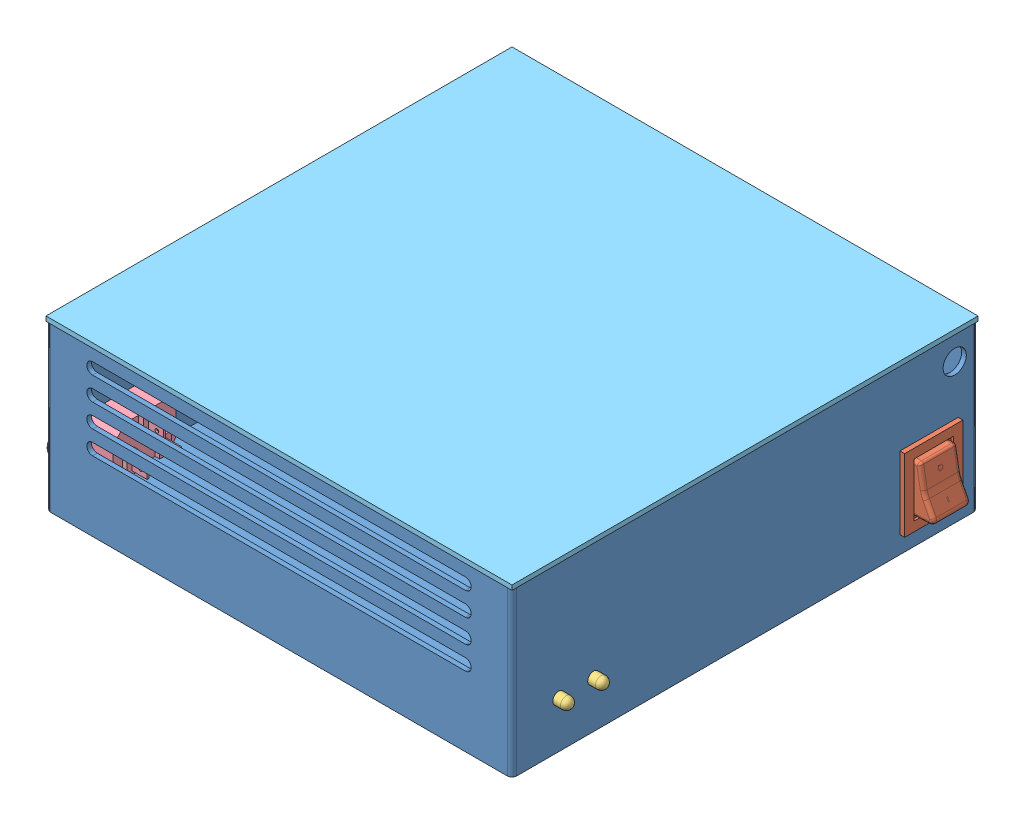
SolidWorks assembly Assem1, configuration Default. Lengths in mm.
Overall size (214.38 72 200).
6 component instances, 5 part files, 13 mates.
Components (placement in the parent):
- base-1: base [Default] at (154.8704 54.4764 92.3221) size (200 70 200)
- KCD4_ROCKET_SWITCH-1: KCD4_ROCKET_SWITCH [Default] at (156.8704 77.4764 113.3221) x (0 0 1) z (0 1 0) size (25 37.48 33.2)
- LED 5mm-1: LED 5mm [Valor predeterminado] at (151.8704 74.4764 257.3221) x (0 -1 0) z (1 0 0) size (10.06 6 40.8)
- LED 5mm-2: LED 5mm [Valor predeterminado] at (151.8704 74.4764 272.3221) x (0 1 0) z (1 0 0) size (10.06 6 40.8)
- AC Power outlet connector-1: AC Power outlet connector [Default] at (-48.4296 74.0764 263.8221) x (0 0 1) z (-1 0 0) size (50 22.4 26.9)
- cover-1: cover [Default] at (148.6869 124.4764 142.5254) size (200 2 200)
Mates (geometry in assembly coordinates):
- Coincident2: coincident anti-aligned: plane of base-1 through (147.8704 90.4764 102.3221) normal (0 0 1); plane of KCD4_ROCKET_SWITCH-1 through (137.1704 90.4764 102.3221) normal (0 0 -1)
- Coincident3: coincident anti-aligned: plane of base-1 through (147.8704 90.4764 124.3221) normal (0 -1 0); plane of KCD4_ROCKET_SWITCH-1 through (137.1704 90.4764 124.3221) normal (0 1 0)
- Coincident4: coincident anti-aligned: plane of base-1 through (154.8704 124.4764 92.3221) normal (1 0 0); plane of KCD4_ROCKET_SWITCH-1 through (154.8704 77.4764 113.3221) normal (-1 0 0)
- Concentric1: concentric anti-aligned: cylinder of base-1 through (147.8704 74.4764 257.3221) axis (1 0 0) radius 2.5; cylinder of LED 5mm-1 through (152.8704 74.4764 257.3221) axis (-1 0 0) radius 2.5
- Coincident6: coincident anti-aligned: plane of base-1 through (152.8704 124.4764 92.3221) normal (-1 0 0); plane of LED 5mm-1 through (152.8704 74.4764 257.3221) normal (1 0 0)
- Concentric2: concentric anti-aligned: cylinder of base-1 through (147.8704 74.4764 272.3221) axis (1 0 0) radius 2.5; cylinder of LED 5mm-2 through (152.8704 74.4764 272.3221) axis (-1 0 0) radius 2.5
- Coincident7: coincident anti-aligned: plane of base-1 through (152.8704 124.4764 92.3221) normal (-1 0 0); plane of LED 5mm-2 through (152.8704 74.4764 272.3221) normal (1 0 0)
- Coincident8: coincident anti-aligned: plane of base-1 through (-38.1296 83.4764 277.3221) normal (0 0 -1); plane of AC Power outlet connector-1 through (-31.3296 64.6764 277.3221) normal (0 0 1)
- Coincident10: coincident anti-aligned: plane of base-1 through (-38.1296 83.4764 250.3221) normal (0 -1 0); plane of AC Power outlet connector-1 through (-31.3296 83.4764 271.7221) normal (0 1 0)
- Coincident11: coincident anti-aligned: plane of base-1 through (-45.1296 124.4764 92.3221) normal (-1 0 0); plane of AC Power outlet connector-1 through (-45.1296 74.0764 263.8221) normal (1 0 0)
- Coincident12: coincident anti-aligned: plane of base-1 through (154.8704 124.4764 92.3221) normal (0 1 0); plane of cover-1 through (148.6869 124.4764 142.5254) normal (0 -1 0)
- Coincident14: coincident aligned: plane of base-1 through (154.8704 124.4764 92.3221) normal (1 0 0); plane of cover-1 through (154.8704 126.4764 92.3221) normal (1 0 0)
- Coincident15: coincident aligned: plane of base-1 through (154.8704 124.4764 292.3221) normal (0 0 1); plane of cover-1 through (-45.1296 126.4764 292.3221) normal (0 0 1)
